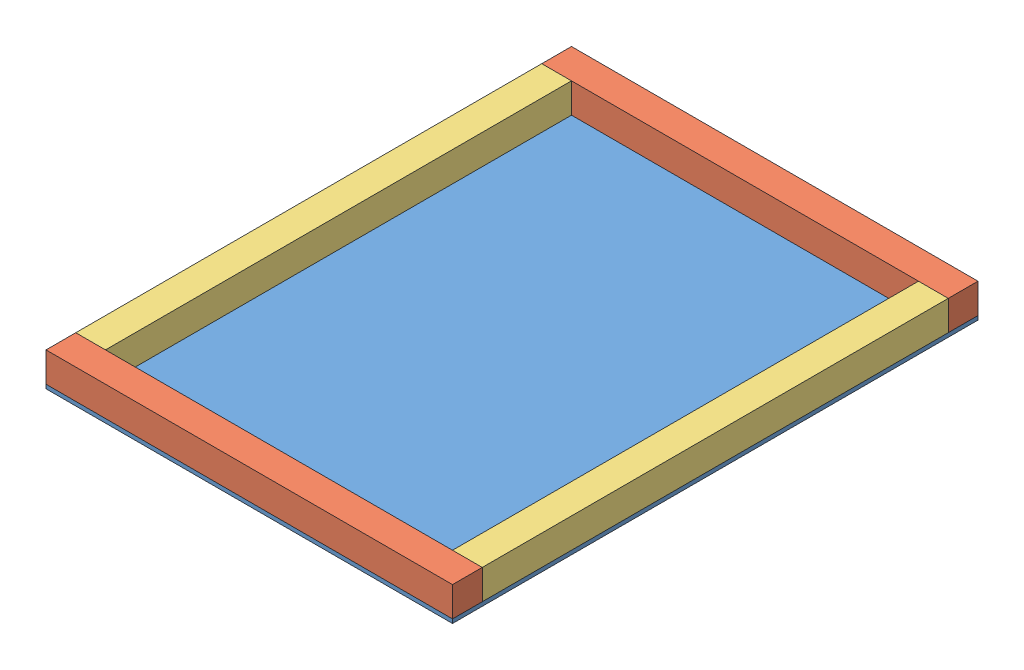
SolidWorks assembly generator_end_wall, configuration Default. Lengths in mm.
Overall size (520.7 43.18 673.1).
5 component instances, 3 part files, 12 mates.
Components (placement in the parent):
- generator_end_wall_plywood-1: generator_end_wall_plywood [Default] at (47.8173 544.5018 492.7253) size (520.7 5.08 673.1)
- 2x2_end_wall_length-1: 2x2_end_wall_length [Default] at (568.5173 549.5818 1127.7253) x (0 1 0) z (0 0 1) size (38.1 520.7 38.1)
- 2x2_side_wall_height-1: 2x2_side_wall_height [Default] at (-599.8827 549.5818 492.7253) x (1 0 0) z (0 1 0) size (38.1 596.9 38.1)
- 2x2_side_wall_height-2: 2x2_side_wall_height [Default] at (-117.2827 549.5818 492.7253) x (1 0 0) z (0 1 0) size (38.1 596.9 38.1)
- 2x2_end_wall_length-2: 2x2_end_wall_length [Default] at (568.5173 549.5818 492.7253) x (0 1 0) z (0 0 1) size (38.1 520.7 38.1)
Mates (geometry in assembly coordinates):
- Coincident1: coincident: plane of generator_end_wall_plywood-1 through (47.8173 549.5818 492.7253) normal (0 1 0); plane of 2x2_end_wall_length-1 through (47.8173 549.5818 1127.7253) normal (0 -1 0)
- Coincident2: coincident: plane of generator_end_wall_plywood-1 through (47.8173 549.5818 1165.8253) normal (0 0 1); plane of 2x2_end_wall_length-1 through (47.8173 549.5818 1165.8253) normal (0 0 1)
- Coincident3: coincident: plane of generator_end_wall_plywood-1 through (47.8173 549.5818 492.7253) normal (-1 0 0); plane of 2x2_end_wall_length-1 through (47.8173 549.5818 1127.7253) normal (-1 0 0)
- Coincident4: coincident: plane of generator_end_wall_plywood-1 through (47.8173 549.5818 492.7253) normal (0 1 0); plane of 2x2_side_wall_height-1 through (-599.8827 549.5818 492.7253) normal (0 -1 0)
- Coincident5: coincident: plane of 2x2_end_wall_length-1 through (47.8173 549.5818 1127.7253) normal (0 0 -1); plane of 2x2_side_wall_height-1 through (85.9173 587.6818 1127.7253) normal (0 0 1)
- Coincident6: coincident: plane of 2x2_end_wall_length-1 through (47.8173 549.5818 1127.7253) normal (-1 0 0); plane of 2x2_side_wall_height-1 through (47.8173 587.6818 530.8253) normal (-1 0 0)
- Coincident7: coincident: plane of generator_end_wall_plywood-1 through (47.8173 549.5818 492.7253) normal (0 1 0); plane of 2x2_side_wall_height-2 through (-117.2827 549.5818 492.7253) normal (0 -1 0)
- Coincident8: coincident: plane of 2x2_end_wall_length-1 through (47.8173 549.5818 1127.7253) normal (0 0 -1); plane of 2x2_side_wall_height-2 through (568.5173 587.6818 1127.7253) normal (0 0 1)
- Coincident9: coincident: plane of 2x2_end_wall_length-1 through (568.5173 549.5818 1127.7253) normal (1 0 0); plane of 2x2_side_wall_height-2 through (568.5173 587.6818 530.8253) normal (1 0 0)
- Coincident10: coincident: plane of generator_end_wall_plywood-1 through (47.8173 549.5818 492.7253) normal (0 1 0); plane of 2x2_end_wall_length-2 through (47.8173 549.5818 492.7253) normal (0 -1 0)
- Coincident11: coincident: plane of 2x2_side_wall_height-1 through (47.8173 587.6818 530.8253) normal (-1 0 0); plane of 2x2_end_wall_length-2 through (47.8173 549.5818 492.7253) normal (-1 0 0)
- Coincident12: coincident: plane of 2x2_side_wall_height-1 through (85.9173 587.6818 530.8253) normal (0 0 -1); plane of 2x2_end_wall_length-2 through (47.8173 549.5818 530.8253) normal (0 0 1)
